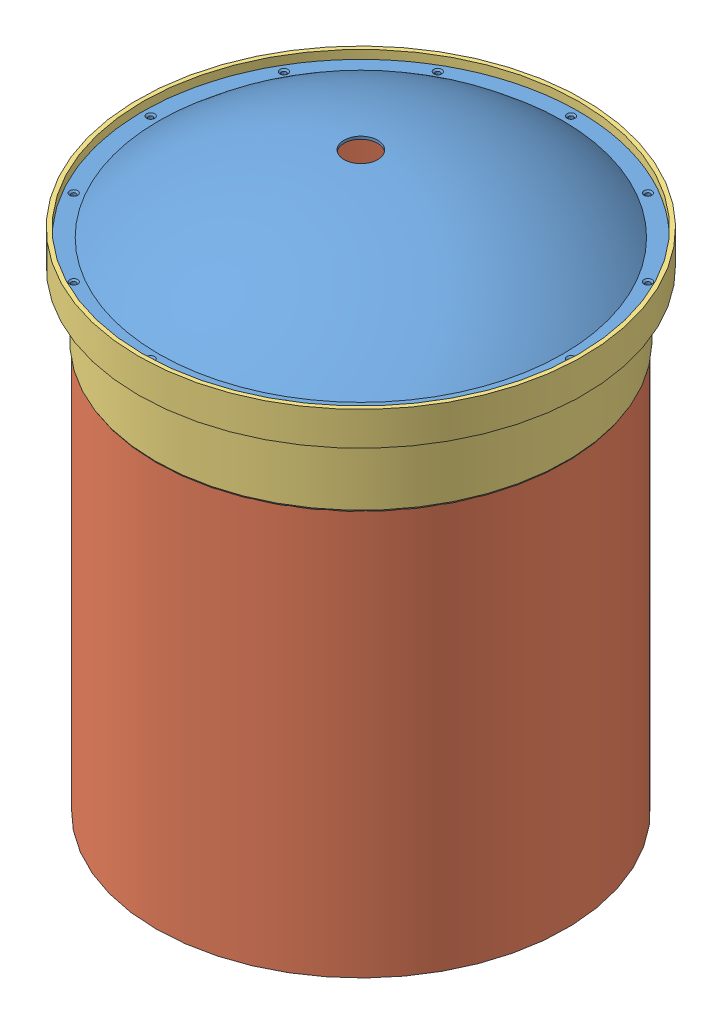
SolidWorks assembly Cryo Tank, configuration Default. Lengths in mm.
Overall size (167.89 215.91 167.89).
4 component instances, 4 part files, 8 mates.
Components (placement in the parent):
- End Cap-1: End Cap [Default] at (48.2444 93.0789 117.7962) size (164.72 31.76 164.72)
- Liner-1: Liner [Default] at (48.2444 0.5797 117.7962) size (154.43 177.8 154.43)
- Main Ring-1: Main Ring [Default] at (48.2444 89.9039 117.7962) size (167.89 38.1 167.89)
- Ring Seal-1: Ring Seal [Default] at (48.2444 89.9039 117.7962) size (164.72 3.17 164.72)
Mates (geometry in assembly coordinates):
- Concentric1: concentric aligned: cylinder of Liner-1 through (48.2444 55.5797 117.7962) axis (0 1 0) radius 77.216; cylinder of Main Ring-1 through (48.2444 144.9039 117.7962) axis (0 1 0) radius 77.216
- Coincident1: coincident anti-aligned: plane of Liner-1 through (124.4444 86.7289 117.7962) normal (0 1 0); plane of Main Ring-1 through (-27.9556 86.7289 117.7962) normal (0 -1 0)
- Concentric2: concentric aligned: cylinder of Liner-1 through (48.2444 55.5797 117.7962) axis (0 1 0) radius 76.2; cylinder of Ring Seal-1 through (48.2444 144.9039 117.7962) axis (0 1 0) radius 76.2
- Coincident2: coincident anti-aligned: plane of Main Ring-1 through (-34.1151 89.9039 117.7962) normal (0 1 0); plane of Ring Seal-1 through (-28.2731 89.9039 117.7962) normal (0 -1 0)
- Concentric3: concentric anti-aligned: cylinder of Main Ring-1 through (-20.4138 89.9039 157.4361) axis (0 1 0) radius 0.5956; cylinder of Ring Seal-1 through (-20.4138 89.9039 157.4361) axis (0 -1 0) radius 1.0922
- Concentric4: concentric aligned: cylinder of End Cap-1 through (48.2444 148.0789 117.7962) axis (0 1 0) radius 82.3595; cylinder of Main Ring-1 through (48.2444 144.9039 117.7962) axis (0 1 0) radius 82.3595
- Coincident3: coincident anti-aligned: plane of End Cap-1 through (-34.1151 93.0789 117.7962) normal (0 -1 0); plane of Ring Seal-1 through (-28.2731 93.0789 117.7962) normal (0 1 0)
- Concentric5: concentric anti-aligned: cylinder of End Cap-1 through (48.2444 96.2539 197.0759) axis (0 1 0) radius 0.889; cylinder of Ring Seal-1 through (48.2444 89.9039 197.0759) axis (0 -1 0) radius 1.0922
